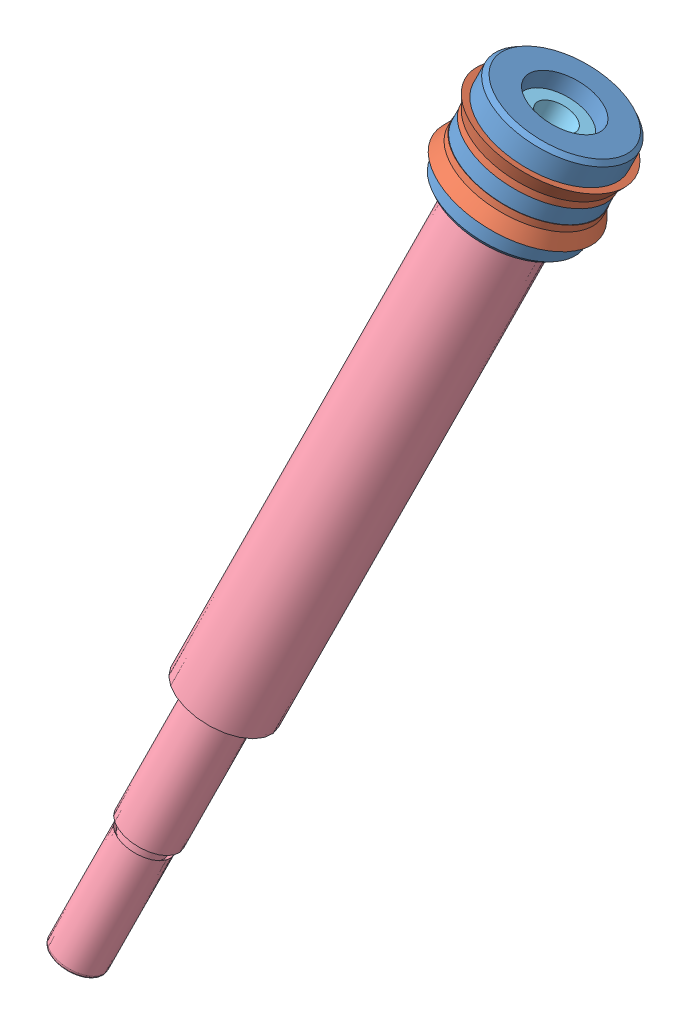
SolidWorks assembly Ensamblaje Piston_Vastago 3, configuration Predeterminado. Lengths in mm.
Overall size (89.72 203.77 87.18).
7 component instances, 6 part files, 11 mates.
Components (placement in the parent):
- Piston-1: Piston [Predeterminado] at (-85.0626 6.0258 71.2952) x (0.951593 -0.303843 0.046372) z (0.04637 0.291064 0.955579) size (31.75 25 31.75)
- sello del piston-1: sello del piston [Predeterminado] at (-83.8472 9.6545 70.1309) x (0.951593 -0.303844 0.046371) z (0.046372 0.291064 0.955579) size (35.1 5 35.1)
- Arandela-1: Arandela [Predeterminado] at (-85.2145 5.5722 71.4407) x (0.951593 -0.303844 0.046371) z (0.046372 0.291064 0.955579) size (15 2 15)
- Vastago-1: Vastago [Predeterminado] at (-99.2773 -36.4143 84.9119) x (0.951593 -0.303844 0.046371) z (0.046372 0.291064 0.955579) size (22 191.5 22)
- sello del piston-3: sello del piston [Predeterminado] at (-85.0626 6.0258 71.2952) x (0.079578 0.280274 0.956616) z (0.949393 -0.313824 0.012969) size (35.1 5 35.1)
- tornillo-1: tornillo [Predeterminado] at (-88.3775 -3.8713 74.4706) x (0.951593 -0.303844 0.046371) z (0.046372 0.291064 0.955579) size (15.42 35 15.42)
- Oring-2: Oring [Predeterminado] at (-88.2929 -3.619 74.3897) x (0.80861 -0.083997 0.582318) z (-0.503814 0.412291 0.75907) size (19 2.5 19)
Mates (geometry in assembly coordinates):
- Concéntrica2: concentric aligned: cylinder of Piston-1 through (-78.1695 26.6061 64.692) axis (0.303844 0.907172 -0.291064) radius 6.5; cylinder of Vastago-1 through (-90.3185 -9.6664 76.33) axis (0.303844 0.907172 -0.291064) radius 11
- Concéntrica6: concentric aligned: circle of Arandela-1; cylinder of Vastago-1 through (-90.3185 -9.6664 76.33) axis (0.303844 0.907172 -0.291064) radius 11
- Concéntrica8: concentric aligned: cylinder of Piston-1 through (-78.1695 26.6061 64.692) axis (0.303844 0.907172 -0.291064) radius 11.875; cylinder of sello del piston-1 through (-78.1523 26.6575 64.6755) axis (0.303844 0.907172 -0.291064) radius 12
- Concéntrica9: concentric anti-aligned: cylinder of Piston-1 through (-78.1695 26.6061 64.692) axis (0.303844 0.907172 -0.291064) radius 11.875; cylinder of sello del piston-3 through (-90.7575 -10.9772 76.7505) axis (-0.303844 -0.907172 0.291064) radius 12
- Concéntrica10: concentric aligned: cylinder of Vastago-1 through (-90.3185 -9.6664 76.33) axis (0.303844 0.907172 -0.291064) radius 11; cylinder of tornillo-1 through (-80.0583 20.9668 66.5014) axis (0.303844 0.907172 -0.291064) radius 4.5
- Tangente7: tangent: cylinder of Vastago-1 through (-90.3185 -9.6664 76.33) axis (0.303844 0.907172 -0.291064) radius 9.5; torus of Oring-2
- Coincidente2: coincident aligned: plane of Piston-1 through (-79.0292 3.5972 71.7421) normal (0.303844 0.907172 -0.291064); plane of Vastago-1 through (-81.8839 4.5088 71.603) normal (0.303844 0.907172 -0.291064)
- Coincidente4: coincident anti-aligned: plane of Piston-1 through (-79.0292 3.5972 71.7421) normal (0.303844 0.907172 -0.291064); plane of Arandela-1 through (-85.2145 5.5722 71.4407) normal (-0.303844 -0.907172 0.291064)
- Coincidente5: coincident anti-aligned: plane of Arandela-1 through (-84.6068 7.3866 70.8586) normal (0.303844 0.907172 -0.291064); plane of tornillo-1 through (-80.3247 6.0193 71.0672) normal (-0.303844 -0.907172 0.291064)
- Coincidente6: coincident anti-aligned: plane of Piston-1 through (-69.9561 1.2023 72.0313) normal (-0.303844 -0.907172 0.291064); plane of sello del piston-3 through (-84.1077 9.3891 82.7745) normal (0.303844 0.907172 -0.291064)
- Coincidente7: coincident anti-aligned: plane of Piston-1 through (-72.547 6.0463 70.6816) normal (0.303844 0.907172 -0.291064); plane of sello del piston-1 through (-72.4281 6.0084 70.6874) normal (-0.303844 -0.907172 0.291064)
